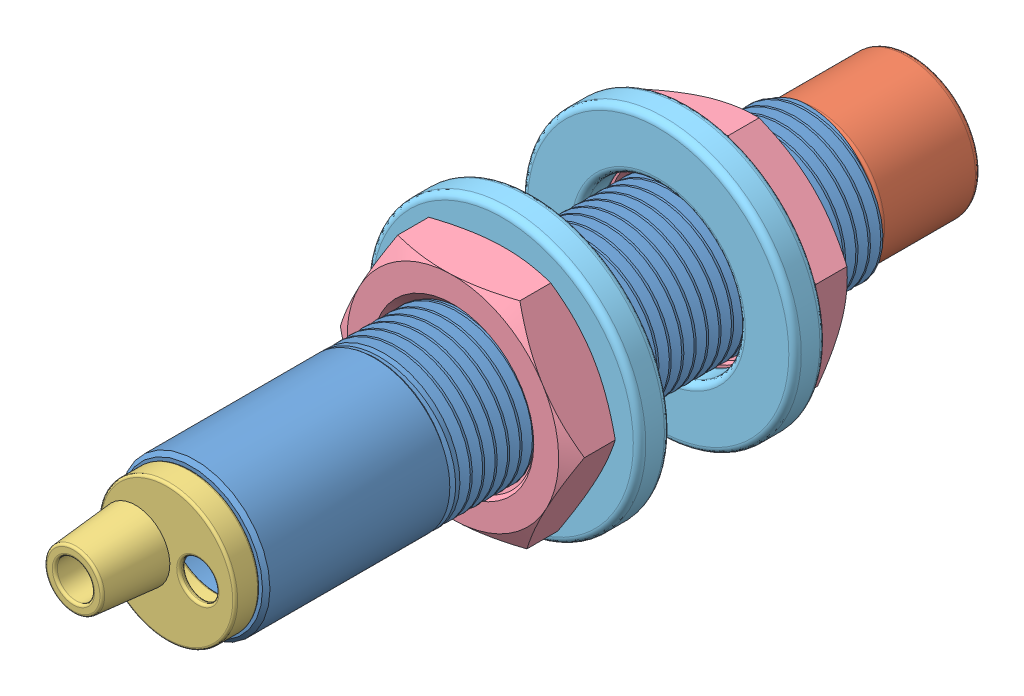
SolidWorks assembly LJ12A3-4-Z-BY, configuration Default. Lengths in mm.
Overall size (28.44 28.44 65).
7 component instances, 5 part files, 12 mates.
Components (placement in the parent):
- LJ12A3-4-Z-BY-1-1: LJ12A3-4-Z-BY-1 [Default] at (0.8756 15.1692 -10.7678) size (12.8 13.04 50.55)
- LJ12A3-4-Z-BY-2-2: LJ12A3-4-Z-BY-2 [Default] at (0.8756 15.1692 -18.7678) x (1 0 0) z (0 1 0) size (11 10 11)
- LJ12A3-4-Z-BY-3-1: LJ12A3-4-Z-BY-3 [Default] at (0.8756 15.1692 41.2322) x (1 0 0) z (0 -1 0) size (11 9 11)
- LJ12A3-4-Z-BY-4-1: LJ12A3-4-Z-BY-4 [Default] at (0.8756 15.1692 -4.7678) x (-0.69421 -0.719772 0) z (0 0 1) size (17 19.63 6)
- LJ12A3-4-Z-BY-5-1: LJ12A3-4-Z-BY-5 [Default] at (0.8756 15.1692 -0.7678) size (22 22 2.5)
- LJ12A3-4-Z-BY-5-2: LJ12A3-4-Z-BY-5 [Default] at (0.8756 15.1692 11.7322) x (-0.933046 0.359756 0) z (0 0 1) size (22 22 2.5)
- LJ12A3-4-Z-BY-4-2: LJ12A3-4-Z-BY-4 [Default] at (0.8756 15.1692 14.2322) x (0.033197 -0.999449 0) z (0 0 1) size (17 19.63 6)
Mates (geometry in assembly coordinates):
- Coincident1: coincident anti-aligned: plane of LJ12A3-4-Z-BY-1-1 through (0.8756 15.1692 -10.7678) normal (0 0 -1); plane of LJ12A3-4-Z-BY-2-2 through (0.8756 19.6692 -10.7678) normal (0 0 1)
- Concentric1: concentric aligned: cylinder of LJ12A3-4-Z-BY-1-1 through (0.8756 15.1692 39.2322) axis (0 0 -1) radius 4.5; cylinder of LJ12A3-4-Z-BY-2-2 through (0.8756 15.1692 -18.7678) axis (0 0 -1) radius 4.5
- Concentric2: concentric anti-aligned: cylinder of LJ12A3-4-Z-BY-1-1 through (0.8756 15.1692 39.2322) axis (0 0 -1) radius 4.5; cylinder of LJ12A3-4-Z-BY-3-1 through (0.8756 15.1692 41.2322) axis (0 0 1) radius 4.5
- Coincident2: coincident anti-aligned: plane of LJ12A3-4-Z-BY-1-1 through (0.8756 15.1692 39.2322) normal (0 0 1); plane of LJ12A3-4-Z-BY-3-1 through (0.8756 9.6692 39.2322) normal (0 0 -1)
- Concentric3: concentric aligned: cylinder of LJ12A3-4-Z-BY-1-1 through (0.8756 15.1692 39.2322) axis (0 0 -1) radius 6; circle of LJ12A3-4-Z-BY-4-1
- Distance1: distance = 6 mm aligned: plane of LJ12A3-4-Z-BY-1-1 through (0.8756 15.1692 -10.7678) normal (0 0 -1); plane of LJ12A3-4-Z-BY-4-1 through (-6.1889 21.9828 -4.7678) normal (0 0 -1)
- Concentric4: concentric aligned: cylinder of LJ12A3-4-Z-BY-1-1 through (0.8756 15.1692 39.2322) axis (0 0 -1) radius 6; cylinder of LJ12A3-4-Z-BY-5-1 through (0.8756 15.1692 3.7322) axis (0 0 -1) radius 6.5
- Coincident4: coincident anti-aligned: plane of LJ12A3-4-Z-BY-4-1 through (-6.1889 21.9828 1.2322) normal (0 0 1); plane of LJ12A3-4-Z-BY-5-1 through (0.8756 15.1692 1.2322) normal (0 0 -1)
- Concentric5: concentric aligned: cylinder of LJ12A3-4-Z-BY-1-1 through (0.8756 15.1692 39.2322) axis (0 0 -1) radius 6; cylinder of LJ12A3-4-Z-BY-5-2 through (0.8756 15.1692 16.2322) axis (0 0 -1) radius 6.5
- Distance2: distance = 10 mm anti-aligned: plane of LJ12A3-4-Z-BY-5-2 through (0.8756 15.1692 11.7322) normal (0 0 -1); plane of LJ12A3-4-Z-BY-5-1 through (0.8756 15.1692 1.7322) normal (0 0 1)
- Concentric6: concentric anti-aligned: cylinder of LJ12A3-4-Z-BY-1-1 through (0.8756 15.1692 39.2322) axis (0 0 -1) radius 6; circle of LJ12A3-4-Z-BY-4-2
- Coincident6: coincident anti-aligned: plane of LJ12A3-4-Z-BY-5-2 through (0.8756 15.1692 16.2322) normal (0 0 1); plane of LJ12A3-4-Z-BY-4-2 through (-8.9339 14.8433 16.2322) normal (0 0 -1)
